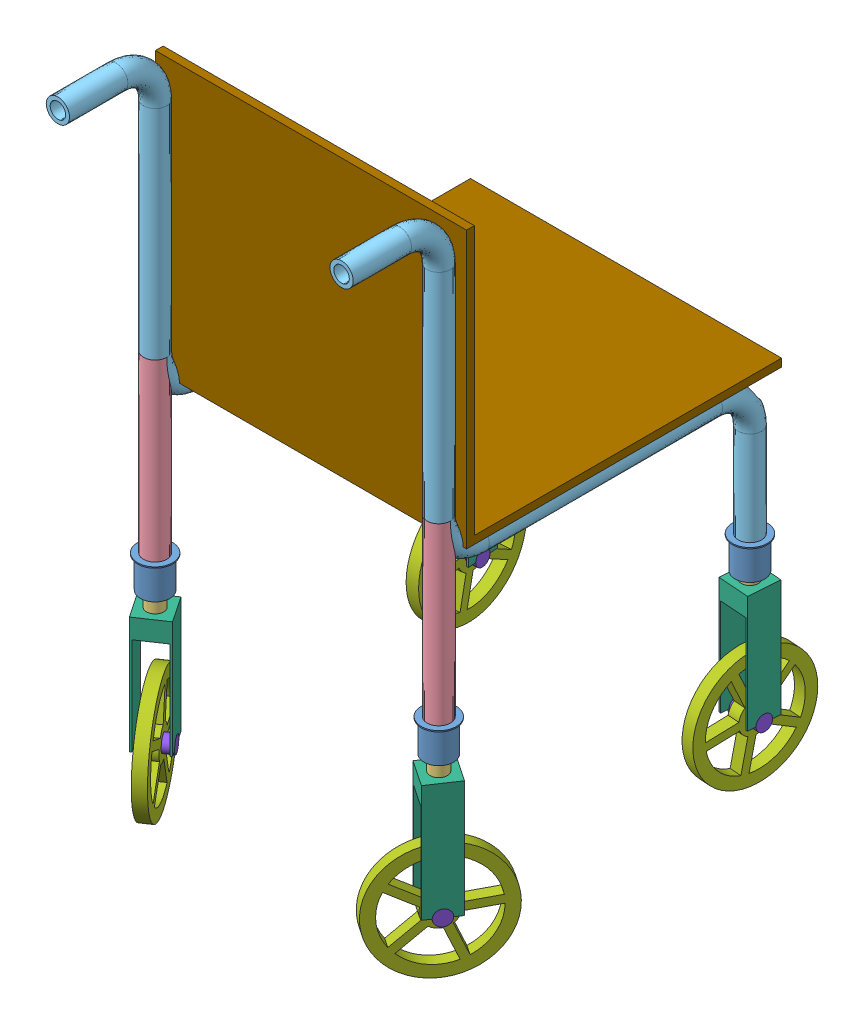
SolidWorks assembly Step_climbing_wheelchair, configuration Default. Lengths in mm.
Overall size (984.86 1767.1 1262.37).
33 component instances, 9 part files, 36 mates.
Components (placement in the parent):
- Part1-1: Part1 [Default] at (-1335.3167 235.5102 -102.0861) x (0 -1 0) z (-0.568138 0 -0.822933) size (83 90 90)
- Part2-1: Part2 [Default] at (-1335.3167 318.7286 -102.0861) x (0 -1 0) z (-0.866706 0 0.498819) size (83 70 70)
- Part3-1: Part3 [Default] at (-1335.3167 514.4799 -102.0861) x (0 -1 0) z (0.952455 0 -0.304678) size (120 54 54)
- fra-1: fra [Default] at (-1335.3167 757.6458 697.9139) size (60 450 60)
- frame-1: frame [Default] at (-1335.3167 657.4677 697.9139) size (60 1140 1080)
- Part3-2: Part3 [Default] at (-1335.3167 506.6154 697.9139) x (0 -1 0) z (-0.92595 0 -0.377645) size (120 54 54)
- Part2-2: Part2 [Default] at (-1335.3167 310.8642 697.9139) x (0 -1 0) z (-0.866706 0 0.498819) size (83 70 70)
- Part1-2: Part1 [Default] at (-1335.3167 227.6458 697.9139) x (0 -1 0) z (-0.568138 0 -0.822933) size (83 90 90)
- rev-1: rev [Default] at (-1302.1519 36.624 720.2768) x (-0.82912 0 -0.559071) z (0.559071 0 -0.82912) size (80 300 80)
- rev-2: rev [Default] at (-1295.4247 64.5722 -99.1487) x (-0.9973 0 -0.073435) z (0.073435 0 -0.9973) size (80 300 80)
- wheel_fr-1: wheel_fr [Default] at (-1347.7535 -113.376 689.5279) x (0.82912 0 0.559071) z (-0.291937 -0.852833 0.432952) size (30 300 300)
- wheel_fr-2: wheel_fr [Default] at (-1320.3572 -85.4278 -100.9845) x (-0.9973 0 -0.073435) z (0.049137 -0.743147 -0.667321) size (30 300 300)
- pin-1: pin [Default] at (-1335.3167 -113.376 697.9139) x (0.82912 0 0.559071) z (-0.559071 0 0.82912) size (40 40 40)
- pin-2: pin [Default] at (-1368.4815 -113.376 675.5511) x (0.82912 0 0.559071) z (-0.559071 0 0.82912) size (40 40 40)
- pin-3: pin [Default] at (-1335.3167 -85.4278 -102.0861) x (-0.9973 0 -0.073435) z (0.073435 0 -0.9973) size (40 40 40)
- pin-4: pin [Default] at (-1295.4247 -85.4278 -99.1487) x (-0.9973 0 -0.073435) z (0.06411 -0.487692 -0.870659) size (40 40 40)
- wheel_fr-3: wheel_fr [Default] at (-2052.2465 -113.376 689.5279) x (-0.82912 0 0.559071) z (-0.291937 0.852833 -0.432952) size (30 300 300)
- pin-5: pin [Default] at (-2064.6833 -113.376 697.9139) x (-0.82912 0 0.559071) z (-0.559071 0 -0.82912) size (40 40 40)
- rev-3: rev [Default] at (-2097.8481 36.624 720.2768) x (0.82912 0 -0.559071) z (0.559071 0 0.82912) size (80 300 80)
- pin-6: pin [Default] at (-2031.5185 -113.376 675.5511) x (-0.82912 0 0.559071) z (-0.559071 0 -0.82912) size (40 40 40)
- Part3-3: Part3 [Default] at (-2064.6833 506.6154 697.9139) x (0 -1 0) z (-0.92595 0 0.377645) size (120 54 54)
- Part2-3: Part2 [Default] at (-2064.6833 310.8642 697.9139) x (0 -1 0) z (-0.866706 0 -0.498819) size (83 70 70)
- Part1-3: Part1 [Default] at (-2064.6833 227.6458 697.9139) x (0 -1 0) z (-0.568138 0 0.822933) size (83 90 90)
- wheel_fr-4: wheel_fr [Default] at (-2079.6428 -85.4278 -100.9845) x (0.9973 0 -0.073435) z (0.049137 0.743147 0.667321) size (30 300 300)
- pin-7: pin [Default] at (-2064.6833 -85.4278 -102.0861) x (0.9973 0 -0.073435) z (0.073435 0 0.9973) size (40 40 40)
- rev-4: rev [Default] at (-2104.5753 64.5722 -99.1487) x (0.9973 0 -0.073435) z (0.073435 0 0.9973) size (80 300 80)
- pin-8: pin [Default] at (-2104.5753 -85.4278 -99.1487) x (0.9973 0 -0.073435) z (0.06411 0.487692 0.870659) size (40 40 40)
- Part3-4: Part3 [Default] at (-2064.6833 514.4799 -102.0861) x (0 -1 0) z (0.952455 0 0.304678) size (120 54 54)
- Part2-4: Part2 [Default] at (-2064.6833 318.7286 -102.0861) x (0 -1 0) z (-0.866706 0 -0.498819) size (83 70 70)
- Part1-4: Part1 [Default] at (-2064.6833 235.5102 -102.0861) x (0 -1 0) z (-0.568138 0 0.822933) size (83 90 90)
- frame-2: frame [Default] at (-2064.6833 657.4677 697.9139) size (60 1140 1080)
- fra-2: fra [Default] at (-2064.6833 757.6458 697.9139) x (-1 0 0) z (0 0 -1) size (60 450 60)
- seat-1: seat [Default] at (-2096.6499 693.4702 655.1963) size (800 710 810)
Mates (geometry in assembly coordinates):
- Concentric1: concentric anti-aligned: cylinder of Part1-1 through (-1335.3167 235.5102 -102.0861) axis (0 -1 0) radius 38; cylinder of Part2-1 through (-1335.3167 318.7286 -102.0861) axis (0 1 0) radius 30
- Concentric2: concentric aligned: cylinder of Part2-1 through (-1335.3167 318.7286 -102.0861) axis (0 1 0) radius 30; cylinder of Part3-1 through (-1335.3167 320.4799 -102.0861) axis (0 1 0) radius 22
- LimitDistance1: limit distance = 5 mm aligned: plane of Part2-1 through (-1321.8486 227.5102 -78.685) normal (0 -1 0); plane of Part1-1 through (-1364.1193 232.5102 -82.2012) normal (0 -1 0)
- Concentric3: concentric aligned: cylinder of Part2-1 through (-1335.3167 318.7286 -102.0861) axis (0 1 0) radius 30; cylinder of Part3-1 through (-1335.3167 320.4799 -102.0861) axis (0 1 0) radius 22
- LimitDistance4: limit distance = 80 mm aligned: plane of Part2-1 through (-1321.8486 227.5102 -78.685) normal (0 -1 0); plane of Part3-1 through (-1343.543 307.5102 -127.8023) normal (0 -1 0)
- Concentric4: concentric aligned: cylinder of fra-1 through (-1335.3167 757.6458 697.9139) axis (0 -1 0) radius 20; circle of frame-1
- Concentric5: concentric aligned: circle of fra-1; cylinder of frame-1 through (-1335.3167 1317.4677 697.9139) axis (0 -1 0) radius 30
- Concentric6: concentric aligned: circle of fra-1; circle of frame-1
- Concentric8: concentric aligned: circle of Part1-1; circle of frame-1
- Concentric9: concentric aligned: circle of Part1-1; circle of frame-1
- Concentric10: concentric aligned: cylinder of Part1-1 through (-1335.3167 235.5102 -102.0861) axis (0 -1 0) radius 38; cylinder of frame-1 through (-1335.3167 557.4677 -102.0861) axis (0 -1 0) radius 30
- LimitDistance5: limit distance = 80 mm aligned: plane of Part2-2 through (-1321.8486 219.6458 721.315) normal (0 -1 0); plane of Part3-2 through (-1345.5131 299.6458 722.9146) normal (0 -1 0)
- LimitDistance6: limit distance = 5 mm aligned: plane of Part2-2 through (-1321.8486 219.6458 721.315) normal (0 -1 0); plane of Part1-2 through (-1364.1193 224.6458 717.7988) normal (0 -1 0)
- Concentric14: concentric anti-aligned: cylinder of Part2-2 through (-1335.3167 310.8642 697.9139) axis (0 1 0) radius 30; cylinder of Part1-2 through (-1335.3167 227.6458 697.9139) axis (0 -1 0) radius 38
- Concentric15: concentric aligned: cylinder of Part3-2 through (-1335.3167 312.6154 697.9139) axis (0 1 0) radius 22; cylinder of Part2-2 through (-1335.3167 310.8642 697.9139) axis (0 1 0) radius 30
- Concentric16: concentric aligned: cylinder of Part3-2 through (-1335.3167 312.6154 697.9139) axis (0 1 0) radius 22; cylinder of Part2-2 through (-1335.3167 310.8642 697.9139) axis (0 1 0) radius 30
- Concentric20: concentric aligned: circle of fra-1; circle of Part1-2
- Lock1: lock: unknown of fra-1; unknown of Part1-2
- Concentric22: concentric aligned: circle of Part3-2; circle of rev-1
- Lock2: lock: unknown of Part3-2; unknown of rev-1
- Concentric29: concentric aligned: circle of Part3-1; circle of rev-2
- Lock3: lock: unknown of Part3-1; unknown of rev-2
- Lock4: lock: unknown of fra-1; unknown of frame-1
- Coincident1: coincident anti-aligned: line of rev-1 through (-1306.2975 -113.376 717.4814) axis (0.82912 0 0.559071); line of wheel_fr-1 through (-1322.8799 -113.376 706.3) axis (-0.82912 0 -0.559071)
- Distance1: distance = 20 mm anti-aligned: plane of wheel_fr-1 through (-1322.8799 -113.376 706.3) normal (0.82912 0 0.559071); plane of rev-1 through (-1328.6603 136.624 750.6462) normal (-0.82912 0 -0.559071)
- Coincident3: coincident aligned: line of rev-2 through (-1375.2087 -85.4278 -105.0234) axis (0.9973 0 0.073435); line of wheel_fr-2 through (-1350.2762 -85.4278 -103.1876) axis (0.9973 0 0.073435)
- Distance2: distance = 20 mm anti-aligned: plane of wheel_fr-2 through (-1350.2762 -85.4278 -103.1876) normal (-0.9973 0 -0.073435); plane of rev-2 through (-1373.1596 164.5722 -64.7643) normal (0.9973 0 0.073435)
- Concentric30: concentric aligned: cylinder of wheel_fr-1 through (-1322.8799 -113.376 706.3) axis (-0.82912 0 -0.559071) radius 20; cylinder of pin-1 through (-1302.1519 -113.376 720.2768) axis (-0.82912 0 -0.559071) radius 20
- Coincident5: coincident aligned: plane of rev-1 through (-1302.1519 -113.376 720.2768) normal (0.82912 0 0.559071); plane of pin-1 through (-1302.1519 -113.376 720.2768) normal (0.82912 0 0.559071)
- Concentric31: concentric aligned: cylinder of wheel_fr-1 through (-1322.8799 -113.376 706.3) axis (-0.82912 0 -0.559071) radius 20; cylinder of pin-2 through (-1335.3167 -113.376 697.9139) axis (-0.82912 0 -0.559071) radius 20
- Coincident6: coincident aligned: plane of rev-1 through (-1368.4815 -113.376 675.5511) normal (-0.82912 0 -0.559071); plane of pin-2 through (-1368.4815 -113.376 675.5511) normal (-0.82912 0 -0.559071)
- Concentric32: concentric aligned: cylinder of wheel_fr-2 through (-1350.2762 -85.4278 -103.1876) axis (0.9973 0 0.073435) radius 20; cylinder of pin-3 through (-1375.2087 -85.4278 -105.0234) axis (0.9973 0 0.073435) radius 20
- Coincident7: coincident aligned: plane of rev-2 through (-1375.2087 -85.4278 -105.0234) normal (-0.9973 0 -0.073435); plane of pin-3 through (-1375.2087 -85.4278 -105.0234) normal (-0.9973 0 -0.073435)
- Concentric33: concentric aligned: cylinder of wheel_fr-2 through (-1350.2762 -85.4278 -103.1876) axis (0.9973 0 0.073435) radius 20; cylinder of pin-4 through (-1335.3167 -85.4278 -102.0861) axis (0.9973 0 0.073435) radius 20
- Coincident8: coincident aligned: plane of rev-2 through (-1295.4247 -85.4278 -99.1487) normal (0.9973 0 0.073435); plane of pin-4 through (-1295.4247 -85.4278 -99.1487) normal (0.9973 0 0.073435)
- GearMate1: gear = 80 : 80 mm: circle of wheel_fr-1; circle of wheel_fr-2
